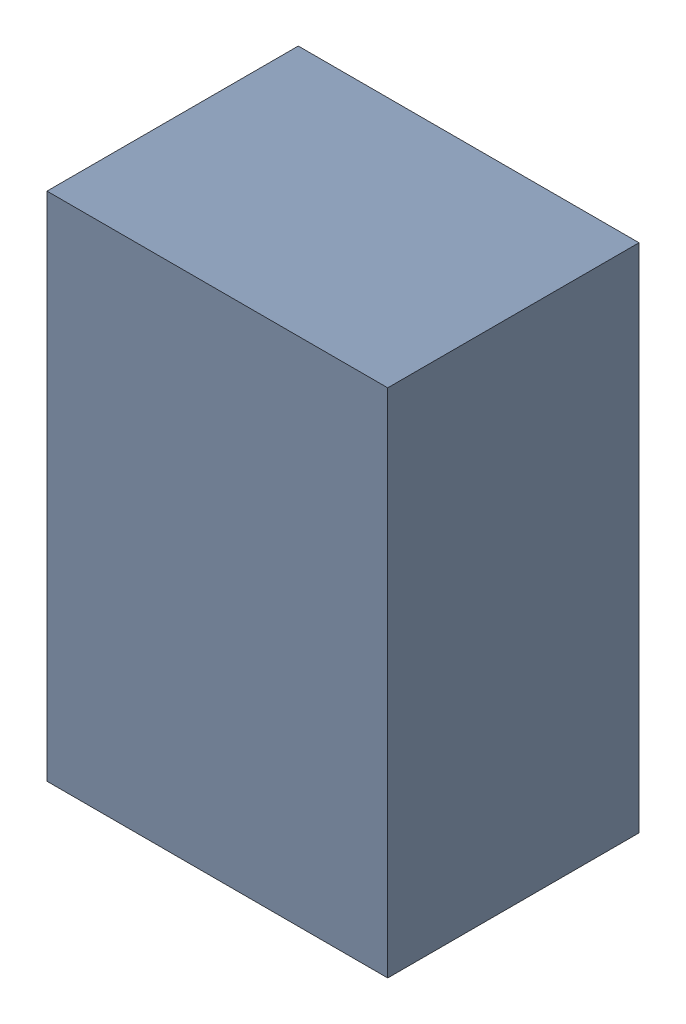
SolidWorks assembly D200, configuration Standard. Lengths in mm.
Overall size (0.8 1.2 0.59).
2 component instances, 1 part files, 0 mates.
Components (placement in the parent):
- 885541832-1: 885541832 [Standard] at (0.55 -14.6032 0) size (0.8 1.2 0.59)
  - Extruded_31-1: Extruded_31 [Standard] at origin size (0.8 1.2 0.59)
